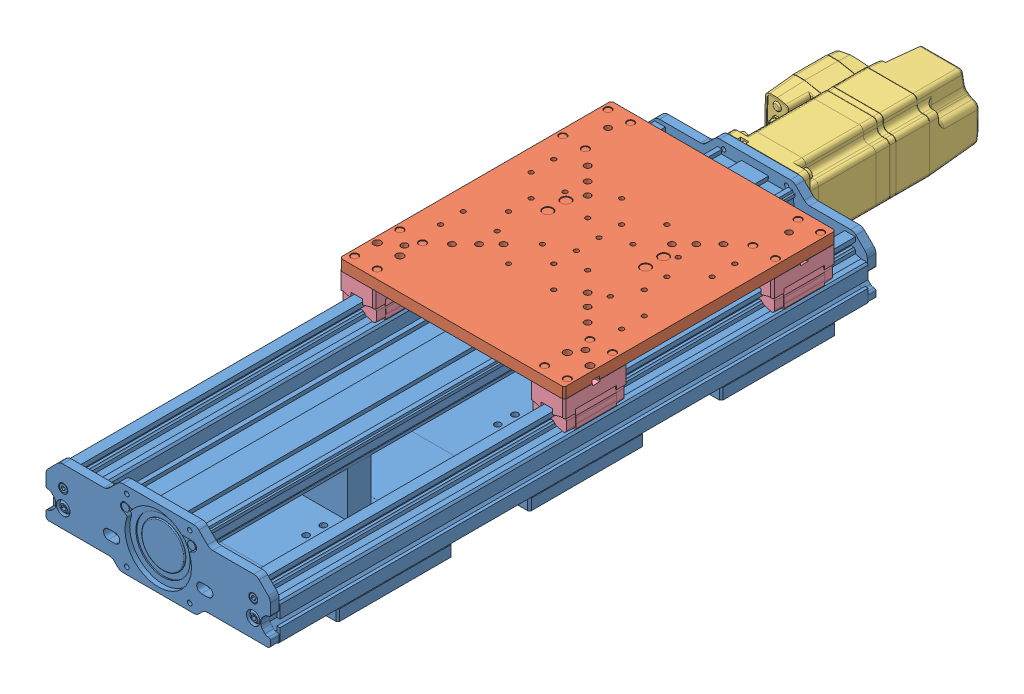
SolidWorks assembly LRU, configuration LRU0250x25-BE01T12A. Lengths in mm.
Overall size (259.25 100 867.72).
9 component instances, 6 part files, 24 mates.
Components (placement in the parent):
- LRU_base^LRU-2: LRU_base^LRU [LRU0250x25] at origin size (250 88.5 669.05) (virtual)
- LRU_carriage^LRU-2: LRU_carriage^LRU [250] at origin (virtual)
- NMS34_motor^LRU-2: NMS34_motor^LRU [LRU-B] at (0 46 -9.525) (virtual)
- LC40_carriage^LRU-6: LC40_carriage^LRU [Default] at (105 32 300) size (39.3 34.8 70) (virtual)
- LC40_carriage^LRU-12: LC40_carriage^LRU [Default] at (105 32 70) size (39.3 34.8 70) (virtual)
- LC40_carriage^LRU-13: LC40_carriage^LRU [Default] at (-105 32 70) size (39.3 34.8 70) (virtual)
- LC40_carriage^LRU-14: LC40_carriage^LRU [Default] at (-105 32 300) size (39.3 34.8 70) (virtual)
- NMS23_sensor^LRU-2: NMS23_sensor^LRU [Default] at (-125 54 71) x (0 1 0) z (0 0 1) size (6.3 9.25 25) (virtual)
- AP187^LRU-2: AP187^LRU [Default] at (-125 32 80) size (17.85 41 27.65) (virtual)
Mates (geometry in assembly coordinates):
- Coincident1: coincident anti-aligned: plane of LRU_base^LRU-2 through (-115.8 55.8034 -9.525) normal (0 0 -1); plane of NMS34_motor^LRU-2 through (0 46 -9.525) normal (0 0 1)
- Concentric1: concentric: cylinder of LRU_base^LRU-2 through (0 46 -4.275) axis (0 0 -1) radius 36.75; point of NMS34_motor^LRU-2
- Coincident3: coincident anti-aligned: plane of LRU_carriage^LRU-2 through (0 88 0) normal (0 -1 0); plane of LC40_carriage^LRU-6 through (85.7 88 335) normal (0 1 0)
- Parallel1: parallel aligned: plane of LC40_carriage^LRU-6 through (105 32 300) normal (0 0 1); plane of assembly through (0 0 0) normal (0 0 1)
- Concentric2: concentric aligned: cylinder of LRU_carriage^LRU-2 through (117.5 95.5 325) axis (0 1 0) radius 4; cylinder of LC40_carriage^LRU-6 through (117.5 88 325) axis (0 1 0) radius 1.65
- Coincident5: coincident anti-aligned: plane of LRU_carriage^LRU-2 through (0 88 0) normal (0 -1 0); plane of LC40_carriage^LRU-12 through (85.7 88 105) normal (0 1 0)
- Parallel2: parallel aligned: plane of LC40_carriage^LRU-12 through (105 32 70) normal (0 0 1); plane of assembly through (0 0 0) normal (0 0 1)
- Concentric3: concentric aligned: cylinder of LRU_carriage^LRU-2 through (117.5 95.5 95) axis (0 1 0) radius 4; cylinder of LC40_carriage^LRU-12 through (117.5 88 95) axis (0 1 0) radius 1.65
- Coincident6: coincident anti-aligned: plane of LRU_carriage^LRU-2 through (0 88 0) normal (0 -1 0); plane of LC40_carriage^LRU-13 through (-124.3 88 105) normal (0 1 0)
- Parallel3: parallel aligned: plane of LC40_carriage^LRU-13 through (-105 32 70) normal (0 0 1); plane of assembly through (0 0 0) normal (0 0 1)
- Concentric4: concentric aligned: cylinder of LRU_carriage^LRU-2 through (-92.5 95.5 95) axis (0 1 0) radius 4; cylinder of LC40_carriage^LRU-13 through (-92.5 88 95) axis (0 1 0) radius 1.65
- Coincident7: coincident anti-aligned: plane of LRU_carriage^LRU-2 through (0 88 0) normal (0 -1 0); plane of LC40_carriage^LRU-14 through (-124.3 88 335) normal (0 1 0)
- Parallel4: parallel aligned: plane of LC40_carriage^LRU-14 through (-105 32 300) normal (0 0 1); plane of assembly through (0 0 0) normal (0 0 1)
- Concentric5: concentric aligned: cylinder of LRU_carriage^LRU-2 through (-92.5 95.5 325) axis (0 1 0) radius 4; cylinder of LC40_carriage^LRU-14 through (-92.5 88 325) axis (0 1 0) radius 1.65
- Distance1: distance = 32 mm aligned: plane of AP187^LRU-2 through (-125 32 80) normal (0 1 0); plane of assembly through (0 0 0) normal (0 1 0)
- Coincident9: coincident anti-aligned: plane of LRU_base^LRU-2 through (-125 50 650) normal (-1 0 0); plane of AP187^LRU-2 through (-125 32 80) normal (1 0 0)
- Distance2: distance = 80 mm aligned: plane of AP187^LRU-2 through (-125 32 80) normal (0 0 1); plane of assembly through (0 0 0) normal (0 0 1)
- Coincident11: coincident anti-aligned: plane of NMS23_sensor^LRU-2 through (-131.1 54 71) normal (-1 0 0); plane of AP187^LRU-2 through (-131.1 57.2 92.15) normal (1 0 0)
- Concentric6: concentric: point of NMS23_sensor^LRU-2; cylinder of AP187^LRU-2 through (-123.5 54 71) axis (-1 0 0) radius 1.7
- Parallel5: parallel aligned: plane of NMS23_sensor^LRU-2 through (-125 54 71) normal (0 1 0); plane of assembly through (0 0 0) normal (0 1 0)
- Coincident12: coincident aligned: plane of LRU_carriage^LRU-2 through (0 0 0) normal (1 0 0); plane of assembly through (0 0 0) normal (1 0 0)
- LimitDistance1: limit distance = 0 mm aligned: plane of LRU_carriage^LRU-2 through (0 0 0) normal (0 0 1); plane of assembly through (0 0 0) normal (0 0 1)
- Coincident14: coincident aligned: plane of LRU_carriage^LRU-2 through (0 0 0) normal (0 1 0); plane of assembly through (0 0 0) normal (0 1 0)
- Parallel6: parallel aligned: plane of NMS34_motor^LRU-2 through (0 46 -9.525) normal (0 1 0); plane of assembly through (0 0 0) normal (0 1 0)
